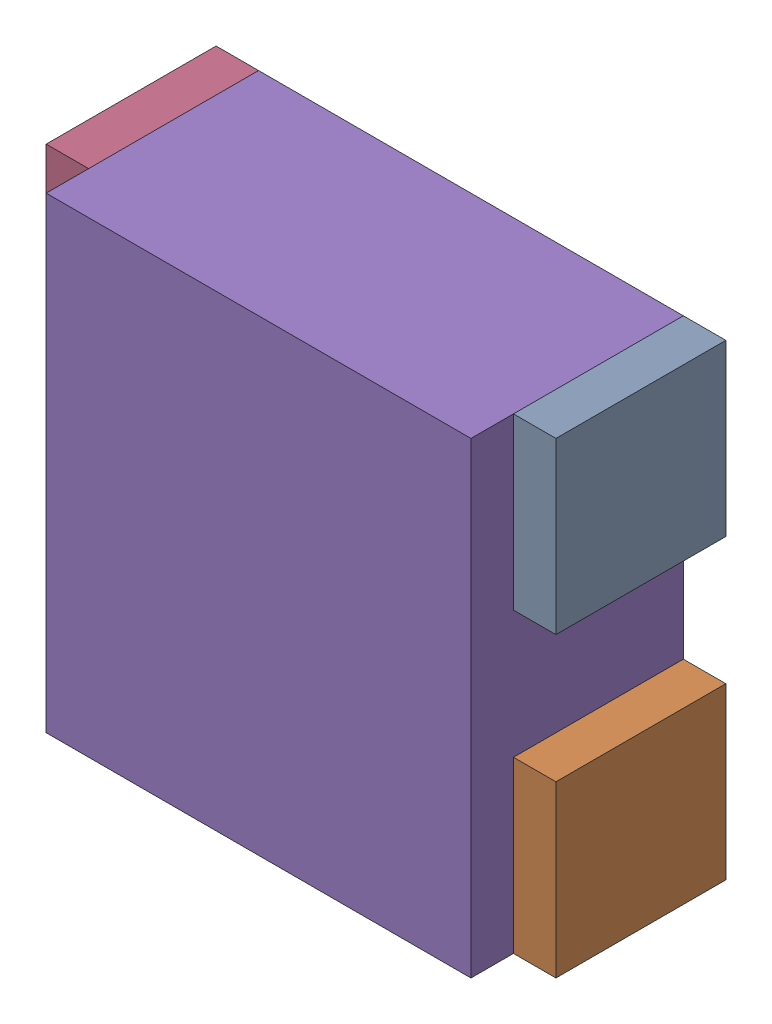
SolidWorks assembly RN7, configuration Default. Lengths in mm.
Overall size (1.2 1.1 0.5).
10 component instances, 2 part files, 0 mates.
Components (placement in the parent):
- 791587232-1: 791587232 [Default] at (131.4 34.4 0) size (0.1 0.4 0.4)
  - Extruded_10-1: Extruded_10 [Default] at origin size (0.1 0.4 0.4)
- 791587232-2: 791587232 [Default] at (131.4 33.7 0) size (0.1 0.4 0.4)
  - Extruded_10-1: Extruded_10 [Default] at origin size (0.1 0.4 0.4)
- 791587232-3: 791587232 [Default] at (130.3 33.7 0) size (0.1 0.4 0.4)
  - Extruded_10-1: Extruded_10 [Default] at origin size (0.1 0.4 0.4)
- 791587232-4: 791587232 [Default] at (130.3 34.4 0) size (0.1 0.4 0.4)
  - Extruded_10-1: Extruded_10 [Default] at origin size (0.1 0.4 0.4)
- 836749552-1: 836749552 [Default] at (130.85 34.05 0) size (1 1.1 0.5)
  - Extruded_11-1: Extruded_11 [Default] at origin size (1 1.1 0.5)
